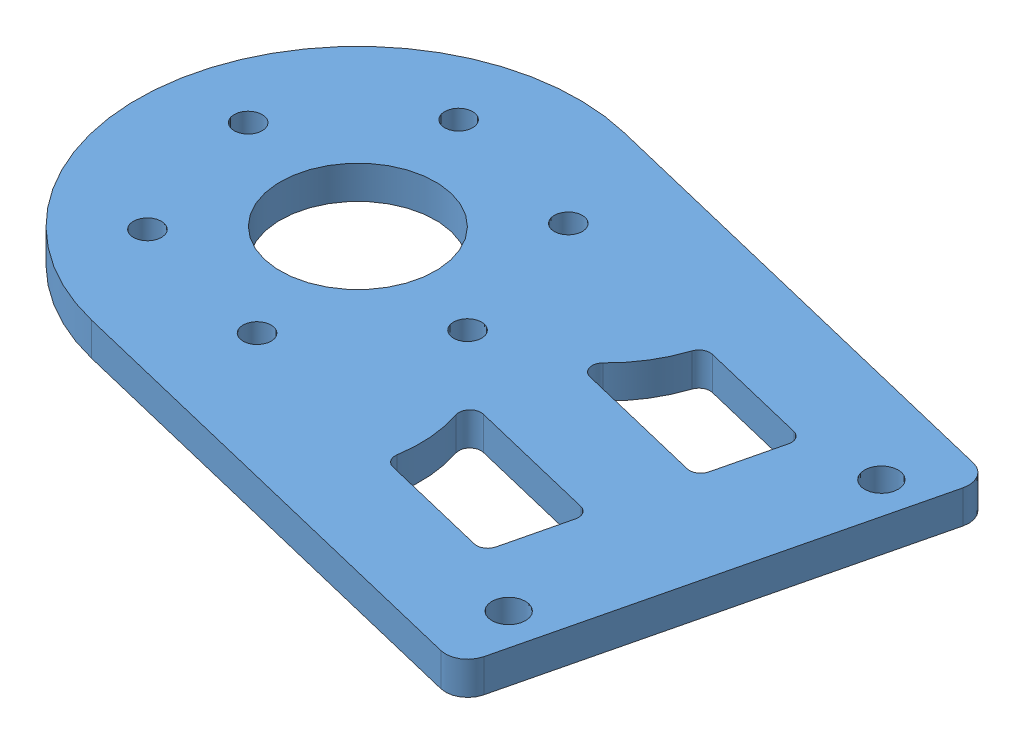
SolidWorks assembly 24joint4, configuration 默认. Lengths in mm.
Overall size (72.58 3 54.16).
2 component instances, 2 part files, 0 mates.
Components (placement in the parent):
- 24joint5连接板双端-1: 24joint5连接板双端 [默认] at (39.4082 60.3881 15.094) x (0.971955 0 0.235167) z (-0.235167 0 0.971955) size (65 3 40)
- 4310 减速电机 3D 20221104_defeature-1: 4310 减速电机 3D 20221104_defeature [默认] at (17.5393 44.9881 9.8027) x (0 0 -1) z (-1 0 0) (suppressed, hidden)
